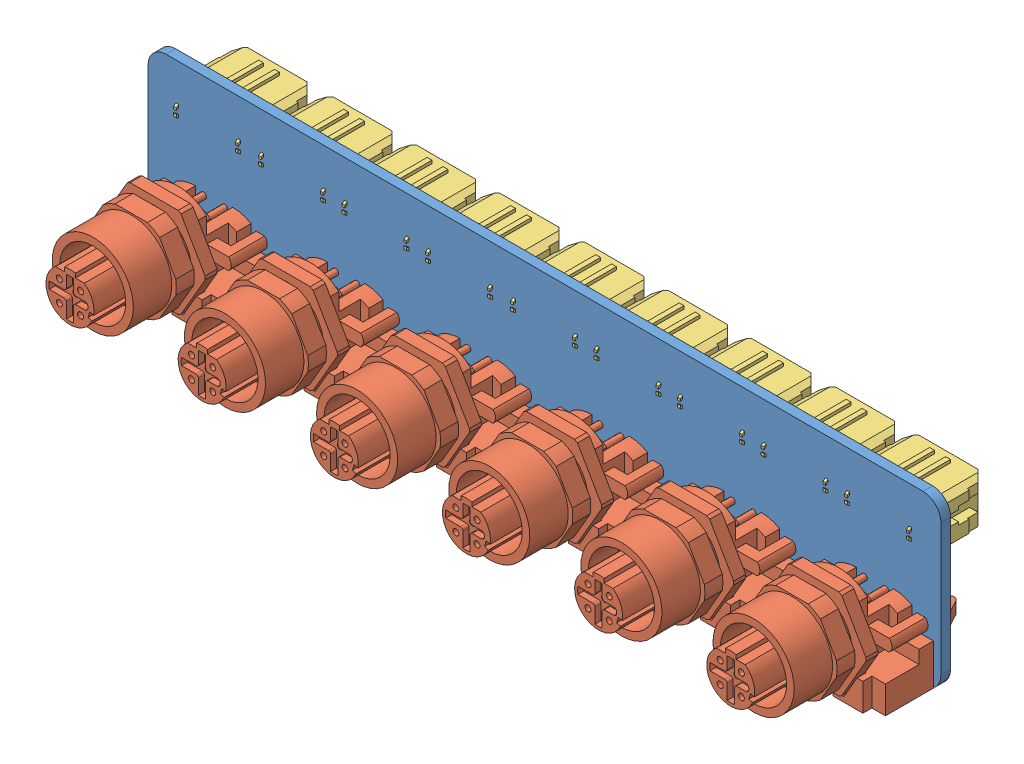
SolidWorks assembly Tank_CAN_Backplane, configuration Default. Lengths in mm.
Overall size (132 28 35.51).
16 component instances, 3 part files, 45 mates.
Components (placement in the parent):
- TCB_PCB-1: TCB_PCB [Default] at (-45.5768 -4.246 -16.093) size (132 28 1.6)
- M12-1: M12 [Défaut] at (-34.5768 4.754 -6.493) x (1 0 0) z (0 1 0) size (20 29.4 16)
- M12-2: M12 [Défaut] at (-12.5768 4.754 -6.493) x (1 0 0) z (0 1 0) size (20 29.4 16)
- M12-3: M12 [Défaut] at (9.4232 4.754 -6.493) x (1 0 0) z (0 1 0) size (20 29.4 16)
- M12-4: M12 [Défaut] at (31.4232 4.754 -6.493) x (1 0 0) z (0 1 0) size (20 29.4 16)
- M12-5: M12 [Défaut] at (53.4232 4.754 -6.493) x (1 0 0) z (0 1 0) size (20 29.4 16)
- Molex MicroFit 6pos vert header - 43045-0615-1: Molex MicroFit 6pos vert header - 43045-0615 [Default] at (76.1482 16.574 -21.053) x (1 0 0) z (0 0 -1) size (13.15 11.2 11.91)
- Molex MicroFit 6pos vert header - 43045-0615-2: Molex MicroFit 6pos vert header - 43045-0615 [Default] at (62.2482 16.574 -21.053) x (1 0 0) z (0 0 -1) size (13.15 11.2 11.91)
- Molex MicroFit 6pos vert header - 43045-0615-3: Molex MicroFit 6pos vert header - 43045-0615 [Default] at (48.3482 16.574 -21.053) x (1 0 0) z (0 0 -1) size (13.15 11.2 11.91)
- Molex MicroFit 6pos vert header - 43045-0615-4: Molex MicroFit 6pos vert header - 43045-0615 [Default] at (34.4482 16.574 -21.053) x (1 0 0) z (0 0 -1) size (13.15 11.2 11.91)
- Molex MicroFit 6pos vert header - 43045-0615-5: Molex MicroFit 6pos vert header - 43045-0615 [Default] at (20.5482 16.574 -21.053) x (1 0 0) z (0 0 -1) size (13.15 11.2 11.91)
- Molex MicroFit 6pos vert header - 43045-0615-6: Molex MicroFit 6pos vert header - 43045-0615 [Default] at (6.3982 16.574 -21.053) x (1 0 0) z (0 0 -1) size (13.15 11.2 11.91)
- Molex MicroFit 6pos vert header - 43045-0615-7: Molex MicroFit 6pos vert header - 43045-0615 [Default] at (-7.5018 16.574 -21.053) x (1 0 0) z (0 0 -1) size (13.15 11.2 11.91)
- Molex MicroFit 6pos vert header - 43045-0615-8: Molex MicroFit 6pos vert header - 43045-0615 [Default] at (-21.4018 16.574 -21.053) x (1 0 0) z (0 0 -1) size (13.15 11.2 11.91)
- Molex MicroFit 6pos vert header - 43045-0615-9: Molex MicroFit 6pos vert header - 43045-0615 [Default] at (-35.5518 16.574 -21.053) x (1 0 0) z (0 0 -1) size (13.15 11.2 11.91)
- M12-6: M12 [Défaut] at (75.4232 4.754 -6.493) x (1 0 0) z (0 1 0) size (20 29.4 16)
Mates (geometry in assembly coordinates):
- Coincident1: coincident anti-aligned: plane of TCB_PCB-1 through (83.4232 -1.246 -14.493) normal (0 0 1); plane of M12-1 through (-40.5669 1.1915 -14.493) normal (0 0 -1)
- Concentric1: concentric: point of TCB_PCB-1; cylinder of M12-1 through (-34.5768 4.754 -3.893) axis (0 0 1) radius 6.75
- Parallel1: parallel aligned: plane of TCB_PCB-1 through (-42.5768 -4.246 -14.493) normal (0 -1 0); plane of M12-1 through (-39.3268 -3.746 -6.493) normal (0 -1 0)
- Coincident4: coincident anti-aligned: plane of TCB_PCB-1 through (83.4232 -1.246 -14.493) normal (0 0 1); plane of M12-2 through (-18.5669 1.1915 -14.493) normal (0 0 -1)
- Concentric2: concentric: point of TCB_PCB-1; cylinder of M12-2 through (-12.5768 4.754 -3.893) axis (0 0 1) radius 6.75
- Parallel2: parallel aligned: plane of TCB_PCB-1 through (-42.5768 -4.246 -14.493) normal (0 -1 0); plane of M12-2 through (-17.3268 -3.746 -6.493) normal (0 -1 0)
- Coincident7: coincident anti-aligned: plane of TCB_PCB-1 through (83.4232 -1.246 -14.493) normal (0 0 1); plane of M12-3 through (15.4134 1.1915 -14.493) normal (0 0 -1)
- Concentric3: concentric: point of TCB_PCB-1; cylinder of M12-3 through (9.4232 4.754 -3.893) axis (0 0 1) radius 6.75
- Parallel3: parallel aligned: plane of TCB_PCB-1 through (-42.5768 -4.246 -14.493) normal (0 -1 0); plane of M12-3 through (4.6732 -3.746 -6.493) normal (0 -1 0)
- Coincident10: coincident anti-aligned: plane of TCB_PCB-1 through (83.4232 -1.246 -14.493) normal (0 0 1); plane of M12-4 through (37.4134 1.1915 -14.493) normal (0 0 -1)
- Concentric4: concentric: point of TCB_PCB-1; cylinder of M12-4 through (31.4232 4.754 -3.893) axis (0 0 1) radius 6.75
- Parallel4: parallel aligned: plane of TCB_PCB-1 through (-42.5768 -4.246 -14.493) normal (0 -1 0); plane of M12-4 through (26.6732 -3.746 -6.493) normal (0 -1 0)
- Coincident13: coincident anti-aligned: plane of TCB_PCB-1 through (83.4232 -1.246 -14.493) normal (0 0 1); plane of M12-5 through (59.4134 1.1915 -14.493) normal (0 0 -1)
- Concentric5: concentric: point of TCB_PCB-1; cylinder of M12-5 through (53.4232 4.754 -3.893) axis (0 0 1) radius 6.75
- Parallel5: parallel aligned: plane of TCB_PCB-1 through (-42.5768 -4.246 -14.493) normal (0 -1 0); plane of M12-5 through (48.6732 -3.746 -6.493) normal (0 -1 0)
- Coincident16: coincident anti-aligned: plane of TCB_PCB-1 through (83.4232 -1.246 -16.093) normal (0 0 -1); plane of Molex MicroFit 6pos vert header - 43045-0615-1 through (73.0232 14.724 -16.093) normal (0 0 1)
- Coincident19: coincident anti-aligned: plane of TCB_PCB-1 through (83.4232 -1.246 -16.093) normal (0 0 -1); plane of Molex MicroFit 6pos vert header - 43045-0615-2 through (55.9232 14.724 -16.093) normal (0 0 1)
- Coincident22: coincident anti-aligned: plane of TCB_PCB-1 through (83.4232 -1.246 -16.093) normal (0 0 -1); plane of Molex MicroFit 6pos vert header - 43045-0615-3 through (42.0232 14.724 -16.093) normal (0 0 1)
- Distance5: distance = 3.75 mm aligned: plane of Molex MicroFit 6pos vert header - 43045-0615-3 through (42.0232 20.004 -26.003) normal (0 1 0); plane of TCB_PCB-1 through (-42.5768 23.754 -14.493) normal (0 1 0)
- Distance6: distance = 31.5 mm aligned: plane of Molex MicroFit 6pos vert header - 43045-0615-3 through (54.9232 16.574 -21.053) normal (1 0 0); plane of TCB_PCB-1 through (86.4232 -1.246 -14.493) normal (1 0 0)
- Coincident25: coincident anti-aligned: plane of TCB_PCB-1 through (83.4232 -1.246 -16.093) normal (0 0 -1); plane of Molex MicroFit 6pos vert header - 43045-0615-4 through (28.1232 14.724 -16.093) normal (0 0 1)
- Coincident26: coincident aligned: plane of Molex MicroFit 6pos vert header - 43045-0615-3 through (42.0232 20.004 -26.003) normal (0 1 0); plane of Molex MicroFit 6pos vert header - 43045-0615-4 through (28.1232 20.004 -26.003) normal (0 1 0)
- Distance7: distance = 0.75 mm anti-aligned: plane of Molex MicroFit 6pos vert header - 43045-0615-4 through (41.0232 16.574 -21.053) normal (1 0 0); plane of Molex MicroFit 6pos vert header - 43045-0615-3 through (41.7732 16.574 -21.053) normal (-1 0 0)
- Coincident28: coincident anti-aligned: plane of TCB_PCB-1 through (83.4232 -1.246 -16.093) normal (0 0 -1); plane of Molex MicroFit 6pos vert header - 43045-0615-5 through (14.2232 14.724 -16.093) normal (0 0 1)
- Coincident29: coincident aligned: plane of Molex MicroFit 6pos vert header - 43045-0615-3 through (42.0232 20.004 -26.003) normal (0 1 0); plane of Molex MicroFit 6pos vert header - 43045-0615-5 through (14.2232 20.004 -26.003) normal (0 1 0)
- Distance8: distance = 0.75 mm anti-aligned: plane of Molex MicroFit 6pos vert header - 43045-0615-5 through (27.1232 16.574 -21.053) normal (1 0 0); plane of Molex MicroFit 6pos vert header - 43045-0615-4 through (27.8732 16.574 -21.053) normal (-1 0 0)
- Coincident31: coincident anti-aligned: plane of TCB_PCB-1 through (83.4232 -1.246 -16.093) normal (0 0 -1); plane of Molex MicroFit 6pos vert header - 43045-0615-6 through (0.0732 14.724 -16.093) normal (0 0 1)
- Coincident32: coincident aligned: plane of Molex MicroFit 6pos vert header - 43045-0615-3 through (42.0232 20.004 -26.003) normal (0 1 0); plane of Molex MicroFit 6pos vert header - 43045-0615-6 through (0.0732 20.004 -26.003) normal (0 1 0)
- Distance9: distance = 1 mm anti-aligned: plane of Molex MicroFit 6pos vert header - 43045-0615-6 through (12.9732 16.574 -21.053) normal (1 0 0); plane of Molex MicroFit 6pos vert header - 43045-0615-5 through (13.9732 16.574 -21.053) normal (-1 0 0)
- Coincident33: coincident anti-aligned: plane of TCB_PCB-1 through (83.4232 -1.246 -16.093) normal (0 0 -1); plane of Molex MicroFit 6pos vert header - 43045-0615-7 through (-13.8268 14.724 -16.093) normal (0 0 1)
- Coincident34: coincident aligned: plane of Molex MicroFit 6pos vert header - 43045-0615-3 through (42.0232 20.004 -26.003) normal (0 1 0); plane of Molex MicroFit 6pos vert header - 43045-0615-7 through (-13.8268 20.004 -26.003) normal (0 1 0)
- Distance10: distance = 0.75 mm anti-aligned: plane of Molex MicroFit 6pos vert header - 43045-0615-6 through (-0.1768 16.574 -21.053) normal (-1 0 0); plane of Molex MicroFit 6pos vert header - 43045-0615-7 through (-0.9268 16.574 -21.053) normal (1 0 0)
- Coincident36: coincident anti-aligned: plane of TCB_PCB-1 through (83.4232 -1.246 -16.093) normal (0 0 -1); plane of Molex MicroFit 6pos vert header - 43045-0615-8 through (-27.7268 14.724 -16.093) normal (0 0 1)
- Coincident37: coincident aligned: plane of Molex MicroFit 6pos vert header - 43045-0615-3 through (42.0232 20.004 -26.003) normal (0 1 0); plane of Molex MicroFit 6pos vert header - 43045-0615-8 through (-27.7268 20.004 -26.003) normal (0 1 0)
- Distance11: distance = 0.75 mm anti-aligned: plane of Molex MicroFit 6pos vert header - 43045-0615-8 through (-14.8268 16.574 -21.053) normal (1 0 0); plane of Molex MicroFit 6pos vert header - 43045-0615-7 through (-14.0768 16.574 -21.053) normal (-1 0 0)
- Coincident39: coincident anti-aligned: plane of TCB_PCB-1 through (83.4232 -1.246 -16.093) normal (0 0 -1); plane of Molex MicroFit 6pos vert header - 43045-0615-9 through (-41.8768 14.724 -16.093) normal (0 0 1)
- Coincident40: coincident aligned: plane of Molex MicroFit 6pos vert header - 43045-0615-3 through (42.0232 20.004 -26.003) normal (0 1 0); plane of Molex MicroFit 6pos vert header - 43045-0615-9 through (-41.8768 20.004 -26.003) normal (0 1 0)
- Distance12: distance = 1 mm anti-aligned: plane of Molex MicroFit 6pos vert header - 43045-0615-8 through (-27.9768 16.574 -21.053) normal (-1 0 0); plane of Molex MicroFit 6pos vert header - 43045-0615-9 through (-28.9768 16.574 -21.053) normal (1 0 0)
- Coincident44: coincident anti-aligned: plane of TCB_PCB-1 through (83.4232 -1.246 -14.493) normal (0 0 1); plane of M12-6 through (81.4134 1.1915 -14.493) normal (0 0 -1)
- Concentric6: concentric: point of TCB_PCB-1; cylinder of M12-6 through (75.4232 4.754 9.507) axis (0 0 1) radius 0.5
- Parallel6: parallel aligned: plane of TCB_PCB-1 through (-42.5768 -4.246 -14.493) normal (0 -1 0); plane of M12-6 through (70.6732 -3.746 -6.493) normal (0 -1 0)
- Distance13: distance = 0.75 mm anti-aligned: plane of Molex MicroFit 6pos vert header - 43045-0615-2 through (55.6732 16.574 -21.053) normal (-1 0 0); plane of Molex MicroFit 6pos vert header - 43045-0615-3 through (54.9232 16.574 -21.053) normal (1 0 0)
- Coincident49: coincident aligned: plane of Molex MicroFit 6pos vert header - 43045-0615-2 through (55.9232 20.504 -18.093) normal (0 1 0); plane of Molex MicroFit 6pos vert header - 43045-0615-3 through (42.0232 20.504 -18.093) normal (0 1 0)
- Coincident50: coincident aligned: plane of Molex MicroFit 6pos vert header - 43045-0615-1 through (69.8232 20.504 -18.093) normal (0 1 0); plane of Molex MicroFit 6pos vert header - 43045-0615-2 through (55.9232 20.504 -18.093) normal (0 1 0)
- Distance14: distance = 0.75 mm anti-aligned: plane of Molex MicroFit 6pos vert header - 43045-0615-2 through (68.8232 16.574 -21.053) normal (1 0 0); plane of Molex MicroFit 6pos vert header - 43045-0615-1 through (69.5732 16.574 -21.053) normal (-1 0 0)
